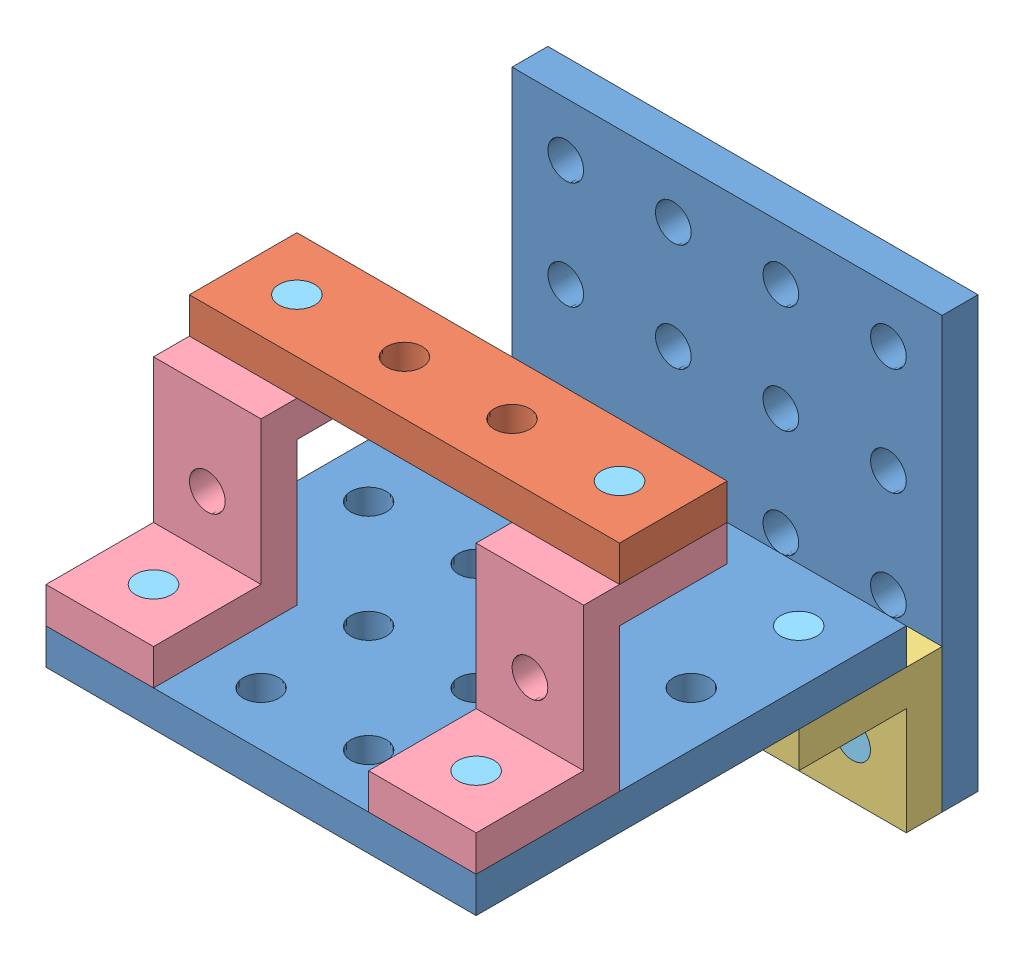
SolidWorks assembly Lab4_Assembly#4_Iddo Sadeh, configuration Default. Lengths in mm.
Overall size (120 120 140).
15 component instances, 5 part files, 16 mates.
Components (placement in the parent):
- PN ME311-5-1: PN ME311-5 [Default] at (7.7444 49.4834 120.5867) size (120 120 10)
- PN ME311-5-2: PN ME311-5 [Default] at (7.7444 99.4834 140.5867) x (1 0 0) z (0 -1 0) size (120 120 10)
- PN ME311-4-1: PN ME311-4 [Default] at (7.7444 159.4834 190.5867) x (1 0 0) z (0 -1 0) size (120 30 10)
- PN BK20-1-1: PN BK20-1 [Default] at (127.7444 89.4834 130.5867) x (0 -1 0) z (-1 0 0) size (40 40 30)
- PN BK20-1-2: PN BK20-1 [Default] at (37.7444 89.4834 130.5867) x (0 -1 0) z (-1 0 0) size (40 40 30)
- PN BK20-2-1: PN BK20-2 [Default] at (97.7444 99.4834 260.5867) size (30 50 70)
- PN BK20-2-2: PN BK20-2 [Default] at (7.7444 99.4834 260.5867) size (30 50 70)
- PG20-1-1: PG20-1 [Default] at (112.7444 99.4834 155.5867) x (0 -1 0) z (0 0 1) size (20 10 10)
- PG20-1-2: PG20-1 [Default] at (22.7444 64.4834 140.5867) x (0 0 -1) z (1 0 0) size (20 10 10)
- PG20-1-3: PG20-1 [Default] at (112.7444 64.4834 140.5867) x (0 0 -1) z (1 0 0) size (20 10 10)
- PG20-1-4: PG20-1 [Default] at (112.7444 109.4834 245.5867) x (0 -1 0) z (0 0 1) size (20 10 10)
- PG20-1-5: PG20-1 [Default] at (22.7444 99.4834 155.5867) x (0 -1 0) z (0 0 1) size (20 10 10)
- PG20-1-6: PG20-1 [Default] at (22.7444 109.4834 245.5867) x (0 -1 0) z (0 0 1) size (20 10 10)
- PG20-1-7: PG20-1 [Default] at (22.7444 139.4834 205.5867) x (0 1 0) z (0 0 1) size (20 10 10)
- PG20-1-8: PG20-1 [Default] at (112.7444 139.4834 205.5867) x (0 1 0) z (0 0 1) size (20 10 10)
Mates (geometry in assembly coordinates):
- Coincident2: coincident aligned: circle of PN ME311-5-1; circle of PN BK20-1-1
- Coincident3: coincident aligned: line of PN ME311-5-1 through (7.7444 49.4834 130.5867) axis (1 0 0); line of PN BK20-1-1 through (97.7444 49.4834 130.5867) axis (1 0 0)
- Coincident7: coincident: line of PN ME311-5-1 through (7.7444 49.4834 130.5867) axis (1 0 0); line of PN BK20-1-2 through (7.7444 49.4834 130.5867) axis (1 0 0)
- Coincident8: coincident aligned: circle of PN ME311-5-1; circle of PN BK20-1-2
- Coincident9: coincident anti-aligned: circle of PN ME311-5-2; circle of PN BK20-1-1
- Coincident10: coincident anti-aligned: circle of PN ME311-5-2; circle of PN BK20-2-2
- Coincident11: coincident anti-aligned: circle of PN ME311-5-2; circle of PN BK20-2-1
- Coincident12: coincident anti-aligned: circle of PN ME311-4-1; circle of PN BK20-2-1
- Coincident13: coincident anti-aligned: circle of PN ME311-4-1; circle of PG20-1-8
- Coincident14: coincident anti-aligned: circle of PN ME311-4-1; circle of PG20-1-7
- Coincident15: coincident anti-aligned: circle of PN BK20-2-2; circle of PG20-1-6
- Coincident16: coincident anti-aligned: circle of PN BK20-2-1; circle of PG20-1-4
- Coincident17: coincident anti-aligned: circle of PN BK20-1-1; circle of PG20-1-1
- Coincident18: coincident anti-aligned: circle of PN BK20-1-2; circle of PG20-1-5
- Coincident19: coincident anti-aligned: circle of PN BK20-1-2; circle of PG20-1-2
- Coincident20: coincident anti-aligned: circle of PN BK20-1-1; circle of PG20-1-3
